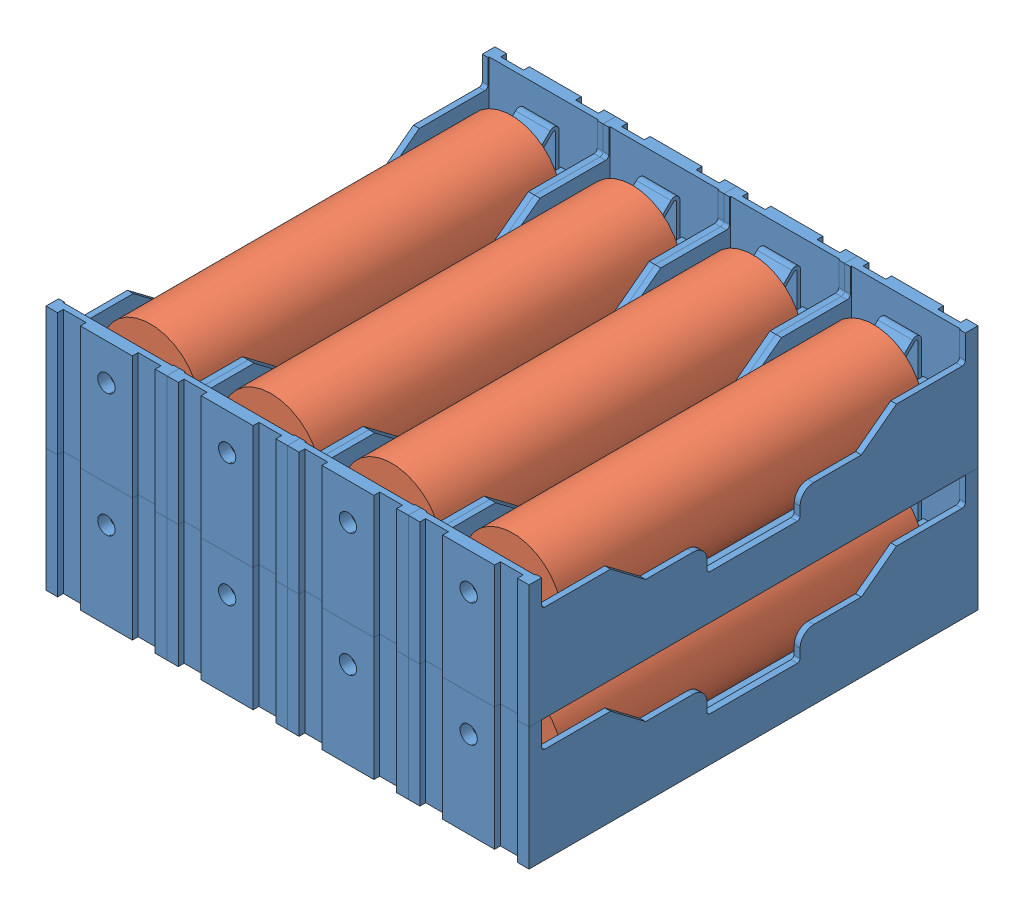
SolidWorks assembly Battery, configuration Default. Lengths in mm.
Overall size (86.9 45.3 77.7).
16 component instances, 2 part files, 41 mates.
Components (placement in the parent):
- Li-Ion_Cell_Holder_BH_18650_A-1: Li-Ion_Cell_Holder_BH_18650_A [Default] at (37.3628 26.3612 65.3908) size (20.9 21.4 77.7)
- 18650 Element-1: 18650 Element [По умолчанию] at (36.5128 36.9612 95.7729) x (-0.879983 -0.475005 0) z (0 0 -1) size (17.2 17.2 64)
- 18650 Element-2: 18650 Element [По умолчанию] at (57.4128 58.2612 95.7729) x (0.979104 -0.20336 0) z (0 0 -1) size (17.2 17.2 64)
- Li-Ion_Cell_Holder_BH_18650_A-2: Li-Ion_Cell_Holder_BH_18650_A [Default] at (58.2628 47.6612 65.3908) size (20.9 21.4 77.7)
- 18650 Element-3: 18650 Element [По умолчанию] at (57.4128 36.9612 95.7729) x (-0.839124 -0.543941 0) z (0 0 -1) size (17.2 17.2 64)
- Li-Ion_Cell_Holder_BH_18650_A-3: Li-Ion_Cell_Holder_BH_18650_A [Default] at (58.2628 26.3612 65.3908) size (20.9 21.4 77.7)
- Li-Ion_Cell_Holder_BH_18650_A-4: Li-Ion_Cell_Holder_BH_18650_A [Default] at (37.3628 47.6612 65.3908) size (20.9 21.4 77.7)
- 18650 Element-4: 18650 Element [По умолчанию] at (36.5128 58.2612 95.7729) x (0.774332 0.63278 0) z (0 0 -1) size (17.2 17.2 64)
- Li-Ion_Cell_Holder_BH_18650_A-5: Li-Ion_Cell_Holder_BH_18650_A [Default] at (79.1628 47.6612 65.3908) size (20.9 21.4 77.7)
- 18650 Element-5: 18650 Element [По умолчанию] at (78.3128 58.2612 95.7729) x (0.774332 0.63278 0) z (0 0 -1) size (17.2 17.2 64)
- Li-Ion_Cell_Holder_BH_18650_A-6: Li-Ion_Cell_Holder_BH_18650_A [Default] at (100.0628 26.3612 65.3908) size (20.9 21.4 77.7)
- 18650 Element-6: 18650 Element [По умолчанию] at (99.2128 36.9612 95.7729) x (-0.43955 0.898218 0) z (0 0 -1) size (17.2 17.2 64)
- Li-Ion_Cell_Holder_BH_18650_A-7: Li-Ion_Cell_Holder_BH_18650_A [Default] at (100.0628 47.6612 65.3908) size (20.9 21.4 77.7)
- 18650 Element-7: 18650 Element [По умолчанию] at (99.2128 58.2612 95.7729) x (0.774332 0.63278 0) z (0 0 -1) size (17.2 17.2 64)
- Li-Ion_Cell_Holder_BH_18650_A-10: Li-Ion_Cell_Holder_BH_18650_A [Default] at (79.1628 26.3612 65.3908) size (20.9 21.4 77.7)
- 18650 Element-10: 18650 Element [По умолчанию] at (78.3128 36.9612 95.7729) x (0.840484 0.541837 0) z (0 0 -1) size (17.2 17.2 64)
Mates (geometry in assembly coordinates):
- Tangent2: tangent anti-aligned: plane of Li-Ion_Cell_Holder_BH_18650_A-1 through (37.3628 28.3612 65.3908) normal (0 1 0); cylinder of 18650 Element-1 through (36.5128 36.9612 31.7729) axis (0 0 1) radius 8.6
- Tangent3: tangent anti-aligned: plane of Li-Ion_Cell_Holder_BH_18650_A-1 through (27.9128 47.6612 104.2408) normal (1 0 0); cylinder of 18650 Element-1 through (36.5128 36.9612 31.7729) axis (0 0 1) radius 8.6
- Coincident7: coincident anti-aligned: plane of Li-Ion_Cell_Holder_BH_18650_A-1 through (40.3628 38.9206 95.7729) normal (0 0 -1); plane of 18650 Element-1 through (36.5128 36.9612 95.7729) normal (0 0 1)
- Tangent4: tangent anti-aligned: cylinder of 18650 Element-2 through (57.4128 58.2612 31.7729) axis (0 0 1) radius 8.6; plane of Li-Ion_Cell_Holder_BH_18650_A-2 through (48.8128 68.9612 104.2408) normal (1 0 0)
- Tangent5: tangent anti-aligned: cylinder of 18650 Element-2 through (57.4128 58.2612 31.7729) axis (0 0 1) radius 8.6; plane of Li-Ion_Cell_Holder_BH_18650_A-2 through (58.2628 49.6612 65.3908) normal (0 1 0)
- Coincident8: coincident anti-aligned: plane of 18650 Element-2 through (57.4128 58.2612 95.7729) normal (0 0 1); plane of Li-Ion_Cell_Holder_BH_18650_A-2 through (61.2628 60.2206 95.7729) normal (0 0 -1)
- Tangent6: tangent anti-aligned: cylinder of 18650 Element-3 through (57.4128 36.9612 31.7729) axis (0 0 1) radius 8.6; plane of Li-Ion_Cell_Holder_BH_18650_A-3 through (48.8128 47.6612 104.2408) normal (1 0 0)
- Tangent7: tangent anti-aligned: cylinder of 18650 Element-3 through (57.4128 36.9612 31.7729) axis (0 0 1) radius 8.6; plane of Li-Ion_Cell_Holder_BH_18650_A-3 through (58.2628 28.3612 65.3908) normal (0 1 0)
- Coincident9: coincident anti-aligned: plane of 18650 Element-3 through (57.4128 36.9612 95.7729) normal (0 0 1); plane of Li-Ion_Cell_Holder_BH_18650_A-3 through (61.2628 38.9206 95.7729) normal (0 0 -1)
- Tangent8: tangent anti-aligned: plane of Li-Ion_Cell_Holder_BH_18650_A-4 through (27.9128 68.9612 104.2408) normal (1 0 0); cylinder of 18650 Element-4 through (36.5128 58.2612 31.7729) axis (0 0 1) radius 8.6
- Tangent9: tangent anti-aligned: plane of Li-Ion_Cell_Holder_BH_18650_A-4 through (37.3628 49.6612 65.3908) normal (0 1 0); cylinder of 18650 Element-4 through (36.5128 58.2612 31.7729) axis (0 0 1) radius 8.6
- Coincident10: coincident anti-aligned: plane of Li-Ion_Cell_Holder_BH_18650_A-4 through (40.3628 60.2206 95.7729) normal (0 0 -1); plane of 18650 Element-4 through (36.5128 58.2612 95.7729) normal (0 0 1)
- Tangent10: tangent anti-aligned: plane of Li-Ion_Cell_Holder_BH_18650_A-5 through (69.7128 68.9612 104.2408) normal (1 0 0); cylinder of 18650 Element-5 through (78.3128 58.2612 31.7729) axis (0 0 1) radius 8.6
- Tangent11: tangent anti-aligned: plane of Li-Ion_Cell_Holder_BH_18650_A-5 through (79.1628 49.6612 65.3908) normal (0 1 0); cylinder of 18650 Element-5 through (78.3128 58.2612 31.7729) axis (0 0 1) radius 8.6
- Coincident11: coincident anti-aligned: plane of Li-Ion_Cell_Holder_BH_18650_A-5 through (82.1628 60.2206 95.7729) normal (0 0 -1); plane of 18650 Element-5 through (78.3128 58.2612 95.7729) normal (0 0 1)
- Tangent12: tangent anti-aligned: plane of Li-Ion_Cell_Holder_BH_18650_A-6 through (90.6128 47.6612 104.2408) normal (1 0 0); cylinder of 18650 Element-6 through (99.2128 36.9612 31.7729) axis (0 0 1) radius 8.6
- Tangent13: tangent anti-aligned: plane of Li-Ion_Cell_Holder_BH_18650_A-6 through (100.0628 28.3612 65.3908) normal (0 1 0); cylinder of 18650 Element-6 through (99.2128 36.9612 31.7729) axis (0 0 1) radius 8.6
- Coincident12: coincident anti-aligned: plane of Li-Ion_Cell_Holder_BH_18650_A-6 through (103.0628 38.9206 95.7729) normal (0 0 -1); plane of 18650 Element-6 through (99.2128 36.9612 95.7729) normal (0 0 1)
- Tangent14: tangent anti-aligned: plane of Li-Ion_Cell_Holder_BH_18650_A-7 through (90.6128 68.9612 104.2408) normal (1 0 0); cylinder of 18650 Element-7 through (99.2128 58.2612 31.7729) axis (0 0 1) radius 8.6
- Tangent15: tangent anti-aligned: plane of Li-Ion_Cell_Holder_BH_18650_A-7 through (100.0628 49.6612 65.3908) normal (0 1 0); cylinder of 18650 Element-7 through (99.2128 58.2612 31.7729) axis (0 0 1) radius 8.6
- Coincident13: coincident anti-aligned: plane of Li-Ion_Cell_Holder_BH_18650_A-7 through (103.0628 60.2206 95.7729) normal (0 0 -1); plane of 18650 Element-7 through (99.2128 58.2612 95.7729) normal (0 0 1)
- Tangent20: tangent anti-aligned: plane of Li-Ion_Cell_Holder_BH_18650_A-10 through (69.7128 47.6612 104.2408) normal (1 0 0); cylinder of 18650 Element-10 through (78.3128 36.9612 31.7729) axis (0 0 1) radius 8.6
- Tangent21: tangent anti-aligned: plane of Li-Ion_Cell_Holder_BH_18650_A-10 through (79.1628 28.3612 65.3908) normal (0 1 0); cylinder of 18650 Element-10 through (78.3128 36.9612 31.7729) axis (0 0 1) radius 8.6
- Coincident16: coincident anti-aligned: plane of Li-Ion_Cell_Holder_BH_18650_A-10 through (82.1628 38.9206 95.7729) normal (0 0 -1); plane of 18650 Element-10 through (78.3128 36.9612 95.7729) normal (0 0 1)
- Coincident22: coincident anti-aligned: plane of Li-Ion_Cell_Holder_BH_18650_A-1 through (47.8128 47.6612 104.2408) normal (1 0 0); plane of Li-Ion_Cell_Holder_BH_18650_A-3 through (47.8128 47.6612 104.2408) normal (-1 0 0)
- Coincident25: coincident aligned: line of Li-Ion_Cell_Holder_BH_18650_A-3 through (68.7128 47.6612 104.2408) axis (0 -1 0); line of Li-Ion_Cell_Holder_BH_18650_A-10 through (68.7128 47.6612 104.2408) axis (0 -1 0)
- Coincident26: coincident aligned: line of Li-Ion_Cell_Holder_BH_18650_A-3 through (68.7128 42.9787 40.6454) axis (0 0 -1); line of Li-Ion_Cell_Holder_BH_18650_A-10 through (68.7128 42.9787 40.6454) axis (0 0 -1)
- Coincident27: coincident aligned: line of Li-Ion_Cell_Holder_BH_18650_A-6 through (89.6128 42.9787 40.6454) axis (0 0 -1); line of Li-Ion_Cell_Holder_BH_18650_A-10 through (89.6128 42.9787 40.6454) axis (0 0 -1)
- Coincident28: coincident aligned: line of Li-Ion_Cell_Holder_BH_18650_A-6 through (89.6128 47.6612 26.5408) axis (0 -1 0); line of Li-Ion_Cell_Holder_BH_18650_A-10 through (89.6128 47.6612 26.5408) axis (0 -1 0)
- Coincident37: coincident aligned: line of Li-Ion_Cell_Holder_BH_18650_A-2 through (47.8128 68.9612 26.5408) axis (0 -1 0); line of Li-Ion_Cell_Holder_BH_18650_A-4 through (47.8128 68.9612 26.5408) axis (0 -1 0)
- Coincident38: coincident aligned: plane of Li-Ion_Cell_Holder_BH_18650_A-2 through (47.8128 64.2787 29.2945) normal (0 1 0); plane of Li-Ion_Cell_Holder_BH_18650_A-4 through (26.9128 64.2787 29.2945) normal (0 1 0)
- Coincident39: coincident aligned: plane of Li-Ion_Cell_Holder_BH_18650_A-2 through (47.8128 64.2787 29.2945) normal (0 1 0); plane of Li-Ion_Cell_Holder_BH_18650_A-5 through (68.7128 64.2787 29.2945) normal (0 1 0)
- Coincident40: coincident: point of Li-Ion_Cell_Holder_BH_18650_A-2; moEndPointRef_w of Li-Ion_Cell_Holder_BH_18650_A-5
- Coincident41: coincident aligned: line of Li-Ion_Cell_Holder_BH_18650_A-2 through (68.7128 64.2787 40.6454) axis (0 0 -1); line of Li-Ion_Cell_Holder_BH_18650_A-5 through (68.7128 64.2787 40.6454) axis (0 0 -1)
- Coincident43: coincident aligned: line of Li-Ion_Cell_Holder_BH_18650_A-5 through (89.6128 64.2787 40.6454) axis (0 0 -1); line of Li-Ion_Cell_Holder_BH_18650_A-7 through (89.6128 64.2787 40.6454) axis (0 0 -1)
- Coincident44: coincident aligned: plane of Li-Ion_Cell_Holder_BH_18650_A-5 through (68.7128 68.9612 26.5408) normal (0 0 -1); plane of Li-Ion_Cell_Holder_BH_18650_A-7 through (89.6128 68.9612 26.5408) normal (0 0 -1)
- Coincident54: coincident anti-aligned: plane of Li-Ion_Cell_Holder_BH_18650_A-1 through (47.8128 47.6612 104.2408) normal (1 0 0); plane of Li-Ion_Cell_Holder_BH_18650_A-3 through (47.8128 47.6612 104.2408) normal (-1 0 0)
- Coincident55: coincident aligned: line of Li-Ion_Cell_Holder_BH_18650_A-1 through (47.8128 47.6612 26.5408) axis (0 -1 0); line of Li-Ion_Cell_Holder_BH_18650_A-3 through (47.8128 47.6612 26.5408) axis (0 -1 0)
- Coincident57: coincident: point of Li-Ion_Cell_Holder_BH_18650_A-1; point of Li-Ion_Cell_Holder_BH_18650_A-3
- Coincident59: coincident aligned: line of Li-Ion_Cell_Holder_BH_18650_A-6 through (104.5628 47.6612 26.5408) axis (-1 0 0); line of Li-Ion_Cell_Holder_BH_18650_A-7 through (104.5628 47.6612 26.5408) axis (-1 0 0)
- Coincident60: coincident aligned: line of Li-Ion_Cell_Holder_BH_18650_A-6 through (110.5128 47.6612 26.5408) axis (0 -1 0); line of Li-Ion_Cell_Holder_BH_18650_A-7 through (110.5128 68.9612 26.5408) axis (0 -1 0)
